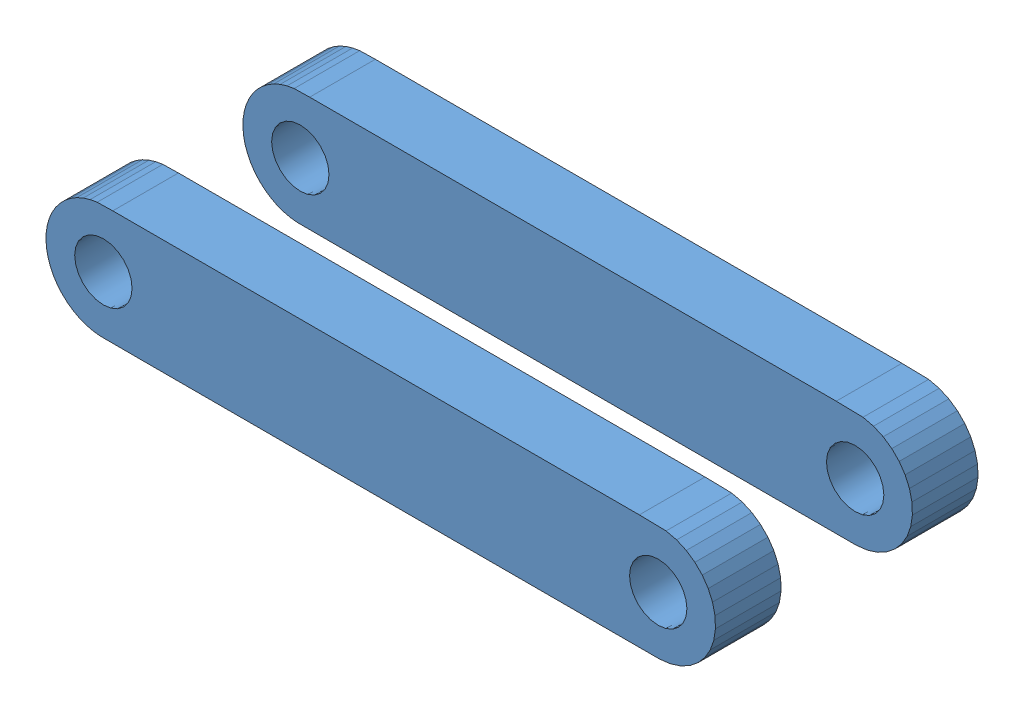
SolidWorks assembly clamp, configuration Default. Lengths in mm.
Overall size (35.69 6.12 14).
2 component instances, 1 part files, 0 mates.
Components (placement in the parent):
- gripper1-1: gripper1 [Default] at origin size (35.69 6.12 3.5)
- gripper1-2: gripper1 [Default] at (0 0 -10.5) size (35.69 6.12 3.5)
